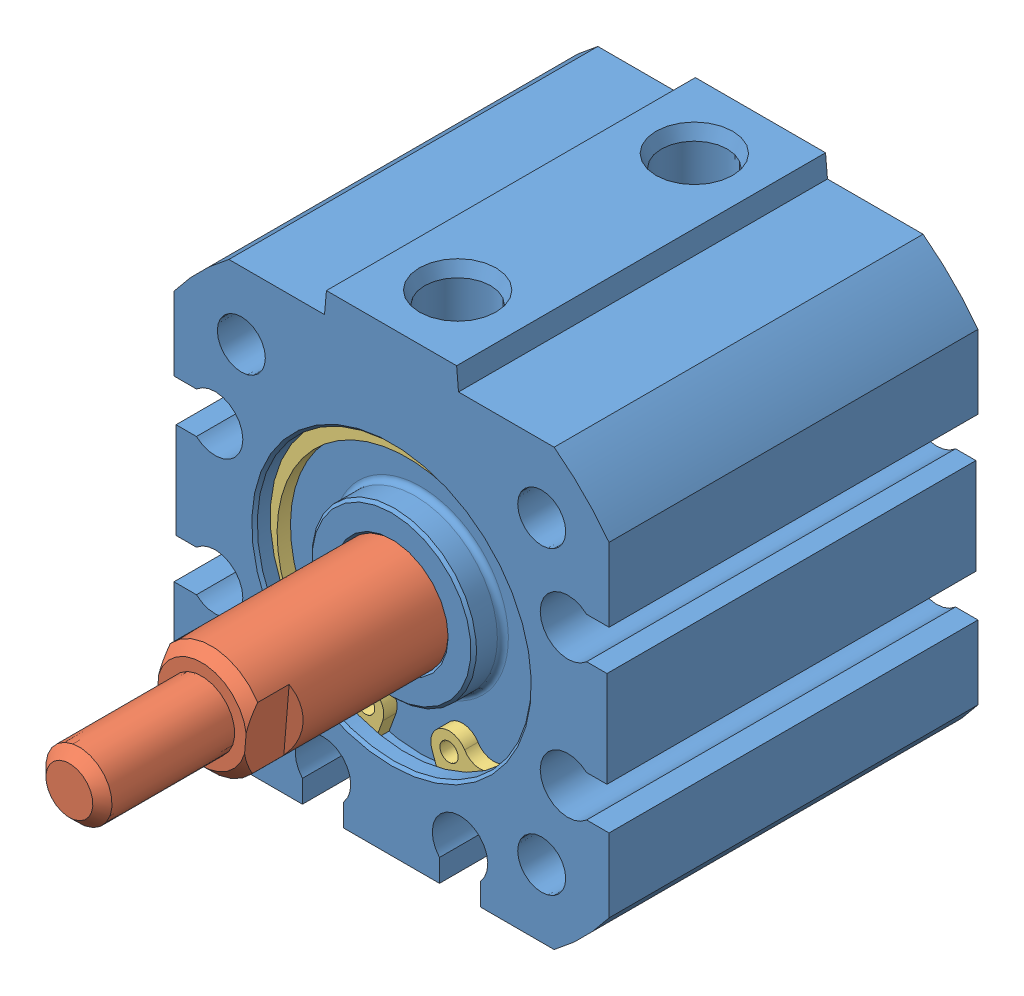
SolidWorks assembly 0.75in bore 0.5in stroke cylinder Vex 217-2778, configuration Default. Lengths in mm.
Overall size (31.75 33.34 50.54).
4 component instances, 4 part files, 5 mates.
Components (placement in the parent):
- 217-2778-NCQ8A075-050M_NCQ8 Tube_075A-1: 217-2778-NCQ8A075-050M_NCQ8 Tube_075A [Default] at origin size (31.75 33.34 26.92)
- 217-2778-NCQ8A075-050M_NCQ8 Rod_075M-1: 217-2778-NCQ8A075-050M_NCQ8 Rod_075M [Default] at (0 0 1.7033) x (-0.996557 0.082913 0) z (0 0 1) size (18.95 18.95 35.27)
- 217-2778-NCQ8A075-050M_Snap Ring_075-1: 217-2778-NCQ8A075-050M_Snap Ring_075 [Default] at (0 0 10.362) size (21 20.74 0.97)
- 217-2778-NCQ8A075-050M_1032_Nut_90545A111-1: 217-2778-NCQ8A075-050M_1032_Nut_90545A111 [Default] at (0 0 36.9693) x (0.866025 0.5 0) z (0 0 1) size (9.53 11 3.39) (suppressed, hidden)
Mates (geometry in assembly coordinates):
- Coincident1: coincident aligned: plane of 217-2778-NCQ8A075-050M_NCQ8 Rod_075M-1 through (0 0 36.9693) normal (0 0 1); plane of 217-2778-NCQ8A075-050M_1032_Nut_90545A111-1 through (2.7496 4.7625 36.9693) normal (0 0 1)
- Concentric1: concentric aligned: cylinder of 217-2778-NCQ8A075-050M_NCQ8 Rod_075M-1 through (0 0 36.9693) axis (0 0 -1) radius 2.413; cone of 217-2778-NCQ8A075-050M_1032_Nut_90545A111-1 through (0 0 36.9693) axis (0 0 -1)
- Coincident2: coincident aligned: plane of 217-2778-NCQ8A075-050M_NCQ8 Rod_075M-1 through (0 0 36.9693) normal (0 0 1); plane of 217-2778-NCQ8A075-050M_1032_Nut_90545A111-1 through (2.7496 4.7625 36.9693) normal (0 0 1)
- LimitDistance1: limit distance = 10.5533 mm anti-aligned: plane of 217-2778-NCQ8A075-050M_NCQ8 Tube_075A-1 through (0 0 -8.85) normal (0 0 1); plane of 217-2778-NCQ8A075-050M_NCQ8 Rod_075M-1 through (0 0 1.7033) normal (0 0 -1)
- Concentric2: concentric aligned: cylinder of 217-2778-NCQ8A075-050M_NCQ8 Tube_075A-1 through (0 0 13.462) axis (0 0 -1) radius 3.937; cylinder of 217-2778-NCQ8A075-050M_NCQ8 Rod_075M-1 through (0 0 38.5433) axis (0 0 -1) radius 3.969
